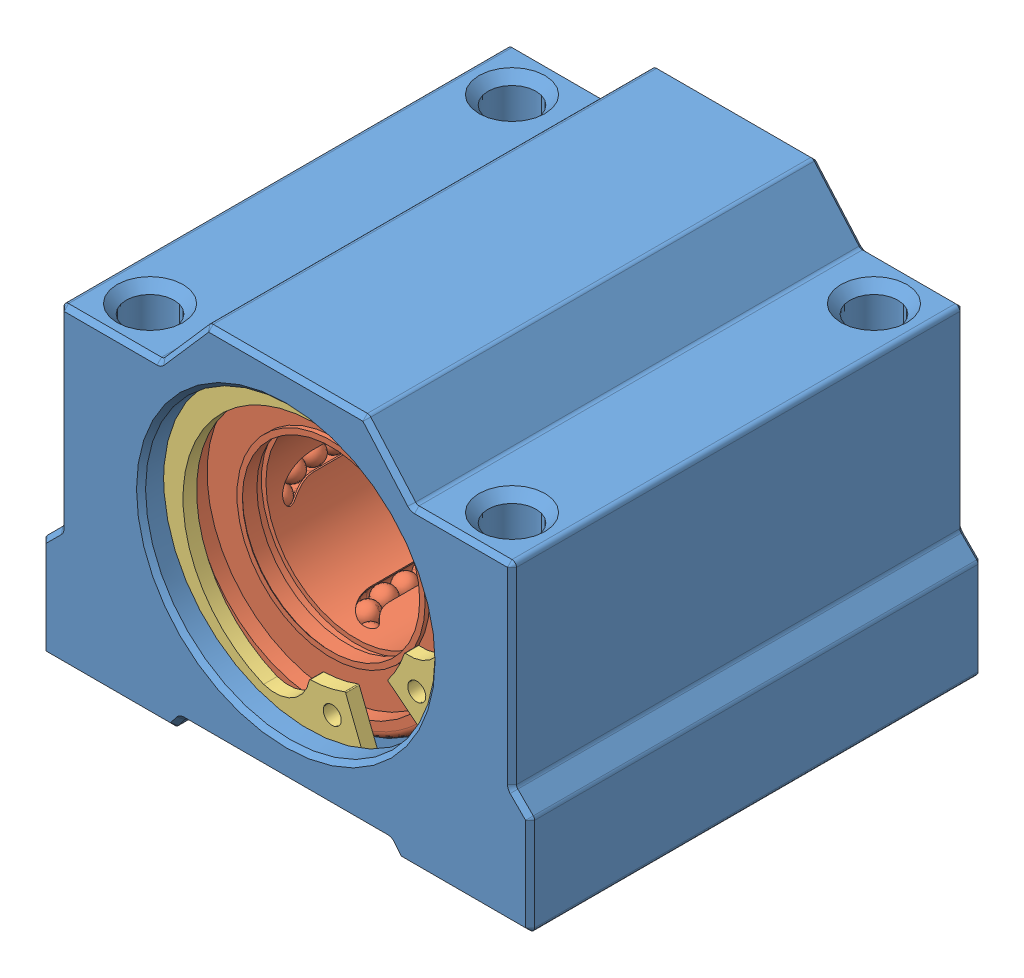
SolidWorks assembly Rodamiento Lineal , configuration По умолчанию. Lengths in mm.
Overall size (54 46.68 50).
4 component instances, 3 part files, 8 mates.
Components (placement in the parent):
- bearing-1: bearing [По умолчанию] at origin size (54 40.5 50)
- Rodamiento LM 20UU-1: Rodamiento LM 20UU [По умолчанию] at (0 0.75 0) size (32 32 42)
- circlip for bores heavy_din-1: circlip for bores heavy_din [Circlip DIN 472 - 32 x 1.5] at (0 0.75 22.5) x (0.803341 0.59552 0) z (0 0 1) size (33.7 33.12 1.5)
- circlip for bores heavy_din-2: circlip for bores heavy_din [Circlip DIN 472 - 32 x 1.5] at (0 0.75 -21) x (0.9907 0.136062 0) z (0 0 1) size (33.7 33.12 1.5)
Mates (geometry in assembly coordinates):
- Совпадение1: coordinate: point of bearing-1; point of assembly
- Концентричный1: concentric anti-aligned: cylinder of bearing-1 through (0 0.75 -25.001) axis (0 0 1) radius 16; cylinder of Rodamiento LM 20UU-1 through (0 0.75 21) axis (0 0 -1) radius 16
- Совпадение2: coincident aligned: plane of bearing-1 through (0 0 0) normal (0 0 1); plane of Rodamiento LM 20UU-1 through (0 0.75 0) normal (0 0 1)
- Совпадение3: coincident aligned: plane of bearing-1 through (0 0 0) normal (1 0 0); plane of Rodamiento LM 20UU-1 through (0 0.75 0) normal (1 0 0)
- Концентричный2: concentric aligned: cylinder of bearing-1 through (0 0.75 25) axis (0 0 1) radius 17; cylinder of circlip for bores heavy_din-1 through (0 0.75 21) axis (0 0 1) radius 16.85
- Концентричный3: concentric aligned: cylinder of bearing-1 through (0 0.75 25) axis (0 0 1) radius 17; cylinder of circlip for bores heavy_din-2 through (0 0.75 -22.5) axis (0 0 1) radius 16.85
- Совпадение7: coincident anti-aligned: plane of bearing-1 through (0 0.75 22.5) normal (0 0 -1); plane of circlip for bores heavy_din-1 through (0 0.75 22.5) normal (0 0 1)
- Совпадение8: coincident anti-aligned: plane of bearing-1 through (0 17.75 -22.5) normal (0 0 1); plane of circlip for bores heavy_din-2 through (0 0.75 -22.5) normal (0 0 -1)
